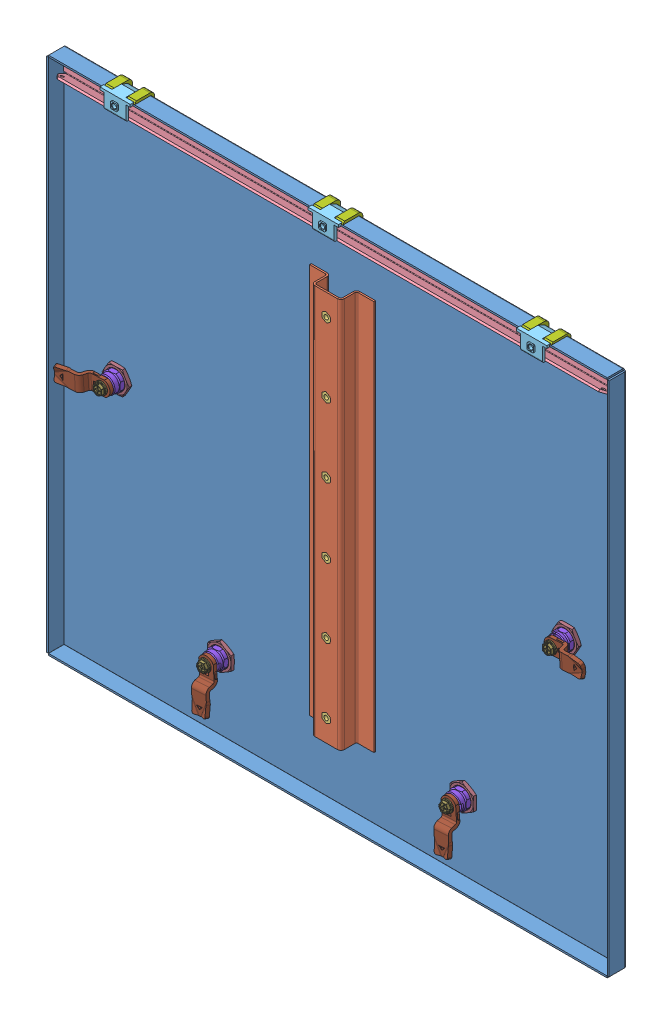
SolidWorks assembly AssemblagePORTE, configuration Défaut. Lengths in mm.
Overall size (648 602 66.85).
55 component instances, 14 part files, 27 mates.
Components (placement in the parent):
- Assemblage-PORTE-OMEGA-1: Assemblage-PORTE-OMEGA [Défaut] at (-31.9244 22.5518 0) size (648 599 22)
  - ENCLOSURE-PORTE-1: ENCLOSURE-PORTE [Défaut] at (-58.8958 24.4108 0) size (648 599 20)
  - Assemblage-ENCLOSURE-OMEGA-1: Assemblage-ENCLOSURE-OMEGA [Défaut] at (-30.8854 309.3758 10.704) x (1 0 0) z (0 -1 0) size (74 20 450)
    - ENCLOSURE-OMEGA-PORTE-1: ENCLOSURE-OMEGA-PORTE [Défaut] at (-28.0104 18.296 0) size (74 20 450)
    - INSERTHM6X30IN-1: INSERTHM6X30IN [Défaut] at (-28.0104 8.896 484.99) size (10 12.4 10.93)
    - INSERTHM6X30IN-2: INSERTHM6X30IN [Défaut] at (-28.0104 8.896 404.98) size (10 12.4 10.93)
    - INSERTHM6X30IN-3: INSERTHM6X30IN [Défaut] at (-28.0104 8.896 324.97) size (10 12.4 10.93)
    - INSERTHM6X30IN-4: INSERTHM6X30IN [Défaut] at (-28.0104 8.896 244.96) size (10 12.4 10.93)
    - INSERTHM6X30IN-5: INSERTHM6X30IN [Défaut] at (-28.0104 8.896 164.95) size (10 12.4 10.93)
    - INSERTHM6X30IN-6: INSERTHM6X30IN [Défaut] at (-28.0104 8.896 84.94) size (10 12.4 10.93)
  - EQUERRE2.5PORTE-1: EQUERRE2.5PORTE [Défaut] at (-58.8958 309.7908 2.5) x (0 1 0) z (0 0 1) size (23.7 640 17.86)
- CH04568150PCL-1: CH04568150PCL [Défaut] at (-91.0702 350.6665 7.0562) x (0 1 0) z (1 0 0) size (21 29.5 62)
  - CH04568150PCLP1-1: CH04568150PCLP1 [Défaut] at (-11.2039 17.4438 0) size (20 26.85 35)
  - CH04568150PCLP3-1: CH04568150PCLP3 [Défaut] at (-12.9368 17.2115 -0.8805) x (0.996722 0.080906 0) z (0 0 1) size (14 6.01 62)
  - CH04568150PCLP2-1: CH04568150PCLP2 [Défaut] at (-11.2039 17.4438 0) size (21 23 35)
- CH04568150PCL-3: CH04568150PCL [Défaut] at (-331.0702 350.6665 7.0562) x (0 1 0) z (1 0 0) size (21 29.5 62)
  - CH04568150PCLP1-1: CH04568150PCLP1 [Défaut] at (-11.2039 17.4438 0) size (20 26.85 35)
  - CH04568150PCLP3-1: CH04568150PCLP3 [Défaut] at (-12.9368 17.2115 -0.8805) x (0.996722 0.080906 0) z (0 0 1) size (14 6.01 62)
  - CH04568150PCLP2-1: CH04568150PCLP2 [Défaut] at (-11.2039 17.4438 0) size (21 23 35)
- AssemblageVERROU316L-1: AssemblageVERROU316L [Défaut] at (168.1798 51.8662 4.8695) x (0 1 0) z (-1 0 0) size (28 37.77 61.63)
  - CO02960130PCL-1: CO02960130PCL [Défaut] at (-4.9037 7.8695 0) size (28 22 28)
  - JOINTVERROU-IP65-1: JOINTVERROU-IP65 [Défaut] at (-4.9037 6.8695 0) x (1 0 0) z (0 1 0) size (27.5 27.5 1)
  - RO02411250CPL-1: RO02411250CPL [Défaut] at (-4.9037 3.4695 0) x (0 1 0) z (-0.064039 0 0.997947) size (25.3 16 16)
  - CA02405480PCcame28-1: CA02405480PCcame28 [Défaut] at (-4.7975 -14.1305 -0.0934) x (0.064039 0 -0.997947) z (0.997947 0 0.064039) size (54.43 17.77 19.1)
  - VISVERROUM6-1: VISVERROUM6 [Défaut] at (-4.9037 -20.1305 0) x (1 0 0) z (0 -1 0) size (13.5 13.5 13.31)
  - ECROUVEROU-1: ECROUVEROU [Défaut] at (-4.9037 0.8695 0) x (1 0 0) z (0 1 0) size (27 31.18 4)
- AssemblageVERROU316L-2: AssemblageVERROU316L [Défaut] at (-349.8202 42.0589 4.8695) x (0 -1 0) z (1 0 0) size (28 37.77 61.63)
  - CO02960130PCL-1: CO02960130PCL [Défaut] at (-4.9037 7.8695 0) size (28 22 28)
  - JOINTVERROU-IP65-1: JOINTVERROU-IP65 [Défaut] at (-4.9037 6.8695 0) x (1 0 0) z (0 1 0) size (27.5 27.5 1)
  - RO02411250CPL-1: RO02411250CPL [Défaut] at (-4.9037 3.4695 0) x (0 1 0) z (-0.064039 0 0.997947) size (25.3 16 16)
  - CA02405480PCcame28-1: CA02405480PCcame28 [Défaut] at (-4.7975 -14.1305 -0.0934) x (0.064039 0 -0.997947) z (0.997947 0 0.064039) size (54.43 17.77 19.1)
  - VISVERROUM6-1: VISVERROUM6 [Défaut] at (-4.9037 -20.1305 0) x (1 0 0) z (0 -1 0) size (13.5 13.5 13.31)
  - ECROUVEROU-1: ECROUVEROU [Défaut] at (-4.9037 0.8695 0) x (1 0 0) z (0 1 0) size (27 31.18 4)
- AssemblageVERROU316L-3: AssemblageVERROU316L [Défaut] at (54.0835 -170.5374 4.8695) x (1 0 0) z (0 1 0) size (28 37.77 61.63)
  - CO02960130PCL-1: CO02960130PCL [Défaut] at (-4.9037 7.8695 0) size (28 22 28)
  - JOINTVERROU-IP65-1: JOINTVERROU-IP65 [Défaut] at (-4.9037 6.8695 0) x (1 0 0) z (0 1 0) size (27.5 27.5 1)
  - RO02411250CPL-1: RO02411250CPL [Défaut] at (-4.9037 3.4695 0) x (0 1 0) z (-0.064039 0 0.997947) size (25.3 16 16)
  - CA02405480PCcame28-1: CA02405480PCcame28 [Défaut] at (-4.7975 -14.1305 -0.0934) x (0.064039 0 -0.997947) z (0.997947 0 0.064039) size (54.43 17.77 19.1)
  - VISVERROUM6-1: VISVERROUM6 [Défaut] at (-4.9037 -20.1305 0) x (1 0 0) z (0 -1 0) size (13.5 13.5 13.31)
  - ECROUVEROU-1: ECROUVEROU [Défaut] at (-4.9037 0.8695 0) x (1 0 0) z (0 1 0) size (27 31.18 4)
- AssemblageVERROU316L-4: AssemblageVERROU316L [Défaut] at (-225.2642 -169.9174 4.8695) x (1 0 0) z (0 1 0) size (28 37.77 61.63)
  - CO02960130PCL-1: CO02960130PCL [Défaut] at (-4.9037 7.8695 0) size (28 22 28)
  - JOINTVERROU-IP65-1: JOINTVERROU-IP65 [Défaut] at (-4.9037 6.8695 0) x (1 0 0) z (0 1 0) size (27.5 27.5 1)
  - RO02411250CPL-1: RO02411250CPL [Défaut] at (-4.9037 3.4695 0) x (0 1 0) z (-0.064039 0 0.997947) size (25.3 16 16)
  - CA02405480PCcame28-1: CA02405480PCcame28 [Défaut] at (-4.7975 -14.1305 -0.0934) x (0.064039 0 -0.997947) z (0.997947 0 0.064039) size (54.43 17.77 19.1)
  - VISVERROUM6-1: VISVERROUM6 [Défaut] at (-4.9037 -20.1305 0) x (1 0 0) z (0 -1 0) size (13.5 13.5 13.31)
  - ECROUVEROU-1: ECROUVEROU [Défaut] at (-4.9037 0.8695 0) x (1 0 0) z (0 1 0) size (27 31.18 4)
- AC04506760PA-1: AC04506760PA [Défaut] at (-349.8202 46.9626 -3) x (0 1 0) z (0 0 1) size (34 38.18 34.08)
- AC04506760PA-2: AC04506760PA [Défaut] at (168.1798 46.9626 -3) x (0 1 0) z (0 0 1) size (34 38.18 34.08)
- AC04506760PA-3: AC04506760PA [Défaut] at (-230.1678 -169.9174 -3) x (0 1 0) z (0 0 1) size (34 38.18 34.08)
- AC04506760PA-4: AC04506760PA [Défaut] at (49.1798 -170.5374 -3) x (0 1 0) z (0 0 1) size (34 38.18 34.08)
- CH04568150PCL-7: CH04568150PCL [Défaut] at (148.9298 349.9165 7.0562) x (0 1 0) z (1 0 0) size (21 29.5 62)
  - CH04568150PCLP1-1: CH04568150PCLP1 [Défaut] at (-11.2039 17.4438 0) size (20 26.85 35)
  - CH04568150PCLP3-1: CH04568150PCLP3 [Défaut] at (-12.9368 17.2115 -0.8805) x (0.996722 0.080906 0) z (0 0 1) size (14 6.01 62)
  - CH04568150PCLP2-1: CH04568150PCLP2 [Défaut] at (-11.2039 17.4438 0) size (21 23 35)
Mates (geometry in assembly coordinates):
- Coïncidente1: coincident anti-aligned: plane of Assemblage-PORTE-OMEGA-1/ENCLOSURE-PORTE-1 through (233.1798 346.4626 -2) normal (0 0 -1); plane of CH04568150PCL-1/CH04568150PCLP2-1 through (-108.5702 336.4626 -2) normal (0 0 1)
- Coïncidente2: coincident anti-aligned: plane of Assemblage-PORTE-OMEGA-1/ENCLOSURE-PORTE-1 through (-414.8202 346.4626 0) normal (0 1 0); plane of CH04568150PCL-1/CH04568150PCLP2-1 through (-108.5702 346.4626 9) normal (0 -1 0)
- Coïncidente3: coincident anti-aligned: plane of Assemblage-PORTE-OMEGA-1/ENCLOSURE-PORTE-1 through (-102.0702 346.4626 0) normal (1 0 0); plane of CH04568150PCL-1/CH04568150PCLP2-1 through (-102.0702 339.2041 2.9413) normal (-1 0 0)
- Coïncidente4: coincident anti-aligned: plane of Assemblage-PORTE-OMEGA-1/ENCLOSURE-PORTE-1 through (233.1798 346.4626 -2) normal (0 0 -1); plane of AssemblageVERROU316L-1/JOINTVERROU-IP65-1 through (168.1798 46.9626 -2) normal (0 0 1)
- Parallèle1: parallel anti-aligned: plane of Assemblage-PORTE-OMEGA-1/ENCLOSURE-PORTE-1 through (157.9298 52.7071 18.001) normal (1 0 0); plane of AssemblageVERROU316L-1/CO02960130PCL-1 through (158.2298 37.0126 -47.1244) normal (-1 0 0)
- Coaxiale1: concentric aligned: cylinder of Assemblage-PORTE-OMEGA-1/ENCLOSURE-PORTE-1 through (168.1798 46.9626 18.001) axis (0 0 -1) radius 11.75; cylinder of AssemblageVERROU316L-1/CO02960130PCL-1 through (168.1798 46.9626 -8.9128) axis (0 0 -1) radius 10.85
- Coïncidente6: coincident anti-aligned: plane of Assemblage-PORTE-OMEGA-1/ENCLOSURE-PORTE-1 through (233.1798 346.4626 -2) normal (0 0 -1); plane of AssemblageVERROU316L-2/JOINTVERROU-IP65-1 through (-349.8202 46.9626 -2) normal (0 0 1)
- Parallèle2: parallel anti-aligned: plane of Assemblage-PORTE-OMEGA-1/ENCLOSURE-PORTE-1 through (-339.5702 52.7071 18.001) normal (-1 0 0); plane of AssemblageVERROU316L-2/CO02960130PCL-1 through (-339.8702 56.9126 -47.1244) normal (1 0 0)
- Coaxiale2: concentric aligned: cylinder of Assemblage-PORTE-OMEGA-1/ENCLOSURE-PORTE-1 through (-349.8202 46.9626 18.001) axis (0 0 -1) radius 11.75; cylinder of AssemblageVERROU316L-2/CO02960130PCL-1 through (-349.8202 46.9626 -8.9128) axis (0 0 -1) radius 10.85
- Coïncidente8: coincident anti-aligned: plane of Assemblage-PORTE-OMEGA-1/ENCLOSURE-PORTE-1 through (233.1798 346.4626 -2) normal (0 0 -1); plane of AssemblageVERROU316L-3/JOINTVERROU-IP65-1 through (49.1798 -170.5374 -2) normal (0 0 1)
- Parallèle3: parallel anti-aligned: plane of Assemblage-PORTE-OMEGA-1/ENCLOSURE-PORTE-1 through (54.9244 -160.2874 18.001) normal (0 -1 0); plane of AssemblageVERROU316L-3/CO02960130PCL-1 through (39.2298 -160.5874 -47.1244) normal (0 1 0)
- Coaxiale3: concentric aligned: cylinder of Assemblage-PORTE-OMEGA-1/ENCLOSURE-PORTE-1 through (49.1798 -170.5374 18.001) axis (0 0 -1) radius 11.75; cylinder of AssemblageVERROU316L-3/CO02960130PCL-1 through (49.1798 -170.5374 -8.9128) axis (0 0 -1) radius 10.85
- Coïncidente10: coincident anti-aligned: plane of Assemblage-PORTE-OMEGA-1/ENCLOSURE-PORTE-1 through (233.1798 346.4626 -2) normal (0 0 -1); plane of AssemblageVERROU316L-4/JOINTVERROU-IP65-1 through (-230.1678 -169.9174 -2) normal (0 0 1)
- Parallèle4: parallel anti-aligned: plane of Assemblage-PORTE-OMEGA-1/ENCLOSURE-PORTE-1 through (-225.0756 -160.2874 18.001) normal (0 -1 0); plane of AssemblageVERROU316L-4/CO02960130PCL-1 through (-240.1178 -159.9674 -47.1244) normal (0 1 0)
- Tangent1: tangent aligned: cylinder of Assemblage-PORTE-OMEGA-1/ENCLOSURE-PORTE-1 through (-230.8202 -170.5374 18.001) axis (0 0 -1) radius 11.75; cylinder of AssemblageVERROU316L-4/CO02960130PCL-1 through (-230.1678 -169.9174 -8.9128) axis (0 0 -1) radius 10.85
- Coïncidente11: coincident anti-aligned: plane of Assemblage-PORTE-OMEGA-1/ENCLOSURE-PORTE-1 through (233.1798 346.4626 -2) normal (0 0 -1); plane of AC04506760PA-1 through (-349.8202 46.9626 -2) normal (0 0 1)
- Coaxiale4: concentric aligned: cylinder of AssemblageVERROU316L-2/CO02960130PCL-1 through (-349.8202 46.9626 -8.9128) axis (0 0 -1) radius 14; cylinder of AC04506760PA-1 through (-349.8202 46.9626 -2) axis (0 0 -1) radius 11
- Parallèle5: parallel aligned: line of Assemblage-PORTE-OMEGA-1/ENCLOSURE-PORTE-1 through (-412.7202 -250.4374 -2) axis (0 1 0); line of AC04506760PA-1 through (-366.6666 44.6826 -8) axis (0 1 0)
- Coïncidente14: coincident anti-aligned: plane of Assemblage-PORTE-OMEGA-1/ENCLOSURE-PORTE-1 through (233.1798 346.4626 -2) normal (0 0 -1); plane of AC04506760PA-3 through (-230.1678 -169.9174 -2) normal (0 0 1)
- Coaxiale7: concentric anti-aligned: cylinder of AssemblageVERROU316L-4/JOINTVERROU-IP65-1 through (-230.1678 -169.9174 -3) axis (0 0 1) radius 13.75; cylinder of AC04506760PA-3 through (-230.1678 -169.9174 -2) axis (0 0 -1) radius 11
- Parallèle6: parallel aligned: line of Assemblage-PORTE-OMEGA-1/ENCLOSURE-PORTE-1 through (-412.7202 -250.4374 -2) axis (0 1 0); line of AC04506760PA-3 through (-247.0143 -172.1973 -8) axis (0 1 0)
- Coïncidente16: coincident anti-aligned: plane of Assemblage-PORTE-OMEGA-1/ENCLOSURE-PORTE-1 through (233.1798 346.4626 -2) normal (0 0 -1); plane of AC04506760PA-4 through (49.1798 -170.5374 -2) normal (0 0 1)
- Coaxiale8: concentric aligned: cylinder of AssemblageVERROU316L-3/CO02960130PCL-1 through (49.1798 -170.5374 -8.9128) axis (0 0 -1) radius 14; cylinder of AC04506760PA-4 through (49.1798 -170.5374 -2) axis (0 0 -1) radius 11
- Parallèle7: parallel aligned: line of Assemblage-PORTE-OMEGA-1/ENCLOSURE-PORTE-1 through (-412.7202 -250.4374 -2) axis (0 1 0); line of AC04506760PA-4 through (32.3334 -172.8174 -8) axis (0 1 0)
- Coïncidente17: coincident anti-aligned: plane of Assemblage-PORTE-OMEGA-1/ENCLOSURE-PORTE-1 through (233.1798 346.4626 -2) normal (0 0 -1); plane of CH04568150PCL-7/CH04568150PCLP2-1 through (131.4298 335.7126 -2) normal (0 0 1)
- Coïncidente18: coincident anti-aligned: plane of Assemblage-PORTE-OMEGA-1/ENCLOSURE-PORTE-1 through (233.1798 331.9626 0) normal (0 1 0); plane of CH04568150PCL-7/CH04568150PCLP2-1 through (137.9298 331.9626 -1) normal (0 -1 0)
- Coïncidente19: coincident anti-aligned: plane of Assemblage-PORTE-OMEGA-1/ENCLOSURE-PORTE-1 through (137.9298 344.4626 0) normal (1 0 0); plane of CH04568150PCL-7/CH04568150PCLP2-1 through (137.9298 338.4541 2.9413) normal (-1 0 0)
